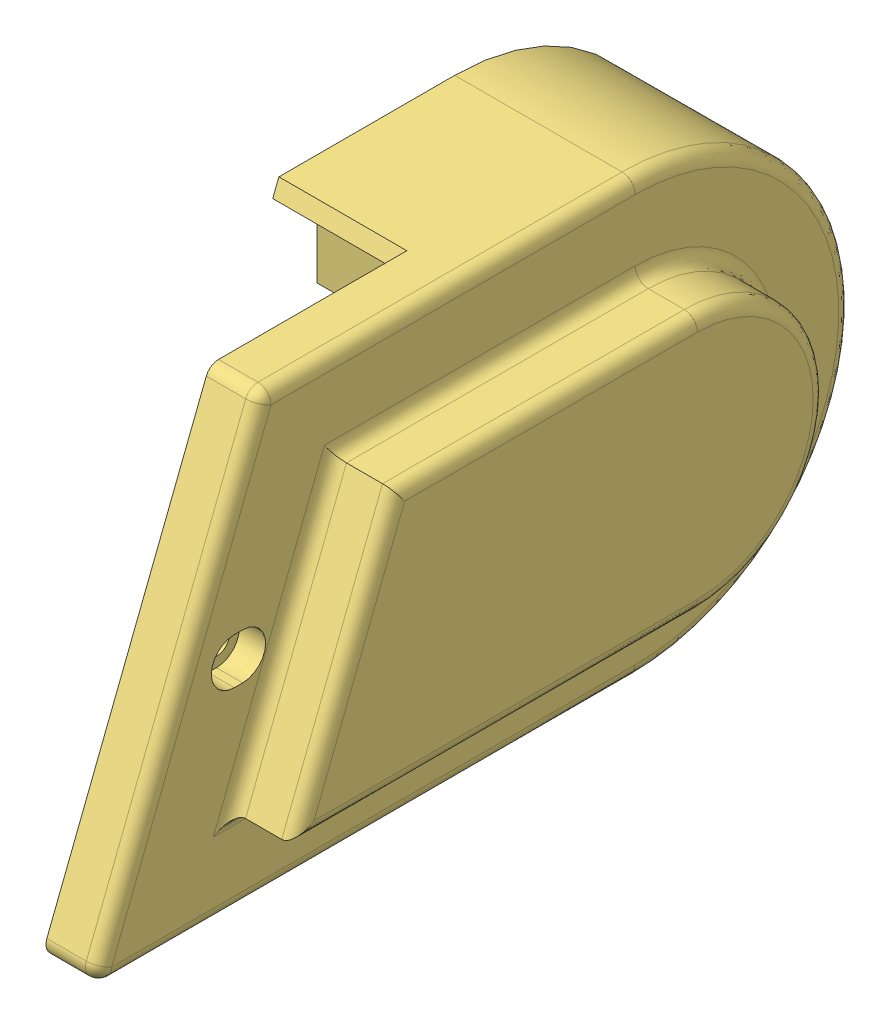
SolidWorks assembly HallEffectSensorMountingAssembly, configuration Default. Lengths in mm.
Overall size (69.97 83.9 145.86).
11 component instances, 7 part files, 26 mates.
Components (placement in the parent):
- Hall_effect_mount-1: Hall_effect_mount [Default] at (-25.3217 0 -65.4431) x (0 1 0) z (0 0 1) size (15.24 44.45 3.43)
- Hall_effect_sensor-1: Hall_effect_sensor [Default] at (-60.3737 0 -62.0141) x (0 1 0) z (1 0 0) size (15.24 6.03 24.38)
- Wheel_Axis_Cover-1: Wheel_Axis_Cover [Default] x (0 0 -1) z (0 -1 0) size (145.34 46.99 83.9)
- 91263A413_ZNC-PLTD ALLOY STL HEX DRIVE FLAT HEAD SCREW-1: 91263A413_ZNC-PLTD ALLOY STL HEX DRIVE FLAT HEAD SCREW [91263A413] at (-67.6127 5.08 -59.5601) x (-0.015431 0.999881 0) z (0 0 1) size (4 4 6.21)
- 91263A413_ZNC-PLTD ALLOY STL HEX DRIVE FLAT HEAD SCREW-2: 91263A413_ZNC-PLTD ALLOY STL HEX DRIVE FLAT HEAD SCREW [91263A413] at (-67.6127 -5.08 -59.5601) x (-0.015431 0.999881 0) z (0 0 1) size (4 4 6.21)
- 94180A307_HEAT-SET INSERTS FOR PLASTICS-1: 94180A307_HEAT-SET INSERTS FOR PLASTICS [Default] at (-67.6127 5.08 -62.0141) x (0.924225 -0.381849 0) z (-0.381849 -0.924225 0) size (3.58 3.11 3.58)
- 94180A307_HEAT-SET INSERTS FOR PLASTICS-2: 94180A307_HEAT-SET INSERTS FOR PLASTICS [Default] at (-67.6127 -5.08 -62.0141) x (0.916807 -0.39933 0) z (-0.39933 -0.916807 0) size (3.58 3.11 3.58)
- 93365A120_HEAT-SET INSERTS FOR PLASTICS (1)-1: 93365A120_HEAT-SET INSERTS FOR PLASTICS (1) [93365A120] at (-41.8317 0 -65.4431) x (-0.994948 -0.100393 0) z (0.100393 -0.994948 0) size (4.37 3.82 4.37)
- 93365A120_HEAT-SET INSERTS FOR PLASTICS (1)-2: 93365A120_HEAT-SET INSERTS FOR PLASTICS (1) [93365A120] at (-29.7667 0 -65.4431) x (-0.966445 -0.256875 0) z (0.256875 -0.966445 0) size (4.37 3.82 4.37)
- 92210A110_18-8 STAINLESS STEEL HEX DRIVE FLAT HEAD SCREW-1: 92210A110_18-8 STAINLESS STEEL HEX DRIVE FLAT HEAD SCREW [92210A110] at (-41.8317 0 -70.8426) x (0 1 0) z (0 0 -1) size (6.48 6.48 13.02)
- 92210A110_18-8 STAINLESS STEEL HEX DRIVE FLAT HEAD SCREW-2: 92210A110_18-8 STAINLESS STEEL HEX DRIVE FLAT HEAD SCREW [92210A110] at (-29.7667 0 -71.1095) x (0.280815 0.959762 0) z (0 0 -1) size (6.48 6.48 13.02)
Mates (geometry in assembly coordinates):
- Coincident1: coincident aligned: plane of Wheel_Axis_Cover-1 through (0 0 0) normal (1 0 0)
- Coincident2: coincident anti-aligned: plane of Wheel_Axis_Cover-1 through (0 0 0) normal (0 0 -1)
- Coincident3: coincident anti-aligned: plane of Wheel_Axis_Cover-1 through (0 0 0) normal (0 -1 0)
- Concentric5: concentric anti-aligned: circle of Hall_effect_sensor-1; cone of 91263A413_ZNC-PLTD ALLOY STL HEX DRIVE FLAT HEAD SCREW-1 through (-67.6127 5.08 -60.7601) axis (0 0 -1)
- Concentric6: concentric anti-aligned: circle of Hall_effect_sensor-1; cone of 91263A413_ZNC-PLTD ALLOY STL HEX DRIVE FLAT HEAD SCREW-2 through (-67.6127 -5.08 -60.7601) axis (0 0 -1)
- Coincident6: coincident anti-aligned: circle of Hall_effect_sensor-1; cone of 91263A413_ZNC-PLTD ALLOY STL HEX DRIVE FLAT HEAD SCREW-2 through (-67.6127 -5.08 -60.7601) axis (0 0 -1)
- Coincident11: coincident aligned: plane of Hall_effect_mount-1 through (-25.3217 0 -65.4431) normal (0 1 0)
- Concentric11: concentric anti-aligned: circle of Hall_effect_sensor-1; cone of 91263A413_ZNC-PLTD ALLOY STL HEX DRIVE FLAT HEAD SCREW-1 through (-67.6127 5.08 -60.7601) axis (0 0 -1)
- Coincident15: coincident anti-aligned: circle of Hall_effect_sensor-1; cone of 91263A413_ZNC-PLTD ALLOY STL HEX DRIVE FLAT HEAD SCREW-1 through (-67.6127 5.08 -60.7601) axis (0 0 -1)
- Coincident20: coincident anti-aligned: plane of Wheel_Axis_Cover-1 through (0 0 0) normal (0 -1 0); plane of 92210A110_18-8 STAINLESS STEEL HEX DRIVE FLAT HEAD SCREW-1 through (-41.8317 0 -70.8426) normal (0 1 0)
- Tangent4: tangent anti-aligned: plane of Wheel_Axis_Cover-1 through (-42.1831 0.1367 -66.9492) normal (-0.002446 -0.754706 -0.656059); cone of 92210A110_18-8 STAINLESS STEEL HEX DRIVE FLAT HEAD SCREW-1 through (-41.8317 0 -68.7344) axis (0 0 1)
- Coincident21: coincident anti-aligned: plane of Hall_effect_mount-1 through (-25.3217 0 -65.4431) normal (0 0 -1); plane of Wheel_Axis_Cover-1 through (-16.383 -7.9375 -65.4431) normal (0 0 1)
- Concentric12: concentric aligned: cylinder of Hall_effect_mount-1 through (-41.8317 0 -62.0141) axis (0 0 -1) radius 2.0193; cylinder of 93365A120_HEAT-SET INSERTS FOR PLASTICS (1)-1 through (-41.8317 0 -62.0141) axis (0 0 -1) radius 1.9431
- Coincident22: coincident aligned: plane of Hall_effect_mount-1 through (-25.3217 0 -65.4431) normal (0 0 -1); plane of 93365A120_HEAT-SET INSERTS FOR PLASTICS (1)-1 through (-41.8317 0 -65.4431) normal (0 0 -1)
- Concentric13: concentric aligned: cylinder of Hall_effect_mount-1 through (-29.7667 0 -62.0141) axis (0 0 -1) radius 2.0193; cylinder of 93365A120_HEAT-SET INSERTS FOR PLASTICS (1)-2 through (-29.7667 0 -62.0141) axis (0 0 -1) radius 1.9431
- Coincident23: coincident aligned: plane of Hall_effect_mount-1 through (-25.3217 0 -65.4431) normal (0 0 -1); plane of 93365A120_HEAT-SET INSERTS FOR PLASTICS (1)-2 through (-29.7667 0 -65.4431) normal (0 0 -1)
- Concentric14: concentric anti-aligned: cylinder of Hall_effect_mount-1 through (-67.6127 -5.08 -62.0141) axis (0 0 -1) radius 1.5; cylinder of 94180A307_HEAT-SET INSERTS FOR PLASTICS-2 through (-67.6127 -5.08 -62.0141) axis (0 0 1) radius 1.482
- Coincident24: coincident aligned: plane of Hall_effect_mount-1 through (-25.3217 0 -62.0141) normal (0 0 1); plane of 94180A307_HEAT-SET INSERTS FOR PLASTICS-2 through (-69.2538 -4.3652 -62.0141) normal (0 0 1)
- Concentric15: concentric anti-aligned: cylinder of Hall_effect_mount-1 through (-67.6127 5.08 -62.0141) axis (0 0 -1) radius 1.5; cylinder of 94180A307_HEAT-SET INSERTS FOR PLASTICS-1 through (-67.6127 5.08 -62.0141) axis (0 0 1) radius 1.482
- Coincident25: coincident aligned: plane of Hall_effect_mount-1 through (-25.3217 0 -62.0141) normal (0 0 1); plane of 94180A307_HEAT-SET INSERTS FOR PLASTICS-1 through (-69.267 5.7635 -62.0141) normal (0 0 1)
- Concentric16: concentric anti-aligned: circle of 93365A120_HEAT-SET INSERTS FOR PLASTICS (1)-1; circle of 92210A110_18-8 STAINLESS STEEL HEX DRIVE FLAT HEAD SCREW-1
- Concentric18: concentric aligned: circle of Hall_effect_mount-1; circle of Hall_effect_sensor-1
- Concentric19: concentric aligned: cylinder of Hall_effect_mount-1 through (-67.6127 5.08 -62.0141) axis (0 0 -1) radius 1.5; cylinder of Hall_effect_sensor-1 through (-67.6127 5.08 -60.4901) axis (0 0 -1) radius 1.27
- Coincident27: coincident anti-aligned: plane of Hall_effect_mount-1 through (-25.3217 0 -62.0141) normal (0 0 1); plane of Hall_effect_sensor-1 through (-60.3737 0 -62.0141) normal (0 0 -1)
- Concentric20: concentric anti-aligned: circle of 93365A120_HEAT-SET INSERTS FOR PLASTICS (1)-2; circle of 92210A110_18-8 STAINLESS STEEL HEX DRIVE FLAT HEAD SCREW-2
- Tangent5: tangent anti-aligned: plane of Wheel_Axis_Cover-1 through (-42.1831 0.1367 -66.9492) normal (0.002446 0.754706 -0.656059); cone of 92210A110_18-8 STAINLESS STEEL HEX DRIVE FLAT HEAD SCREW-2 through (-29.7667 0 -69.0013) axis (0 0 1)
